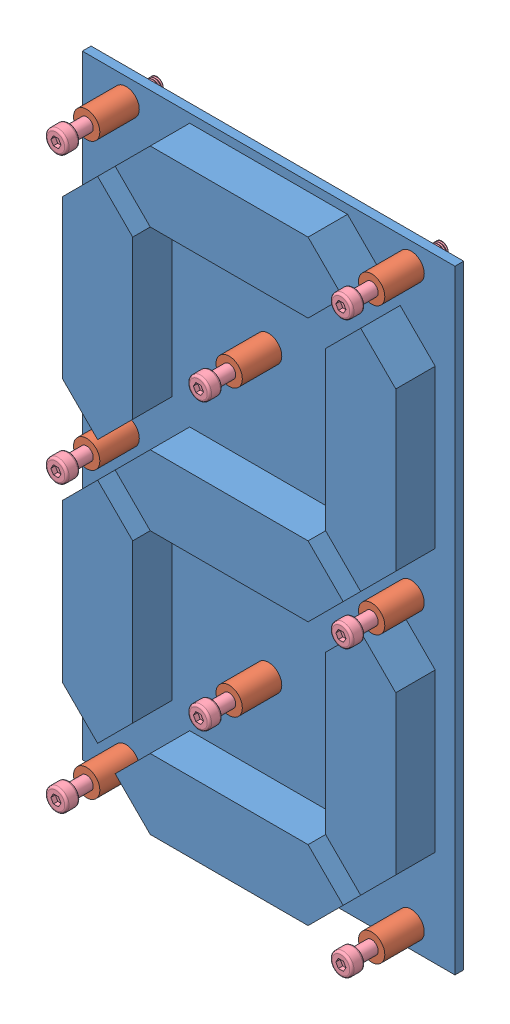
SolidWorks assembly Ensamblaje2, configuration Predeterminado. Lengths in mm.
Overall size (85 140 23).
33 component instances, 4 part files, 6 mates.
Components (placement in the parent):
- Display-1: Display [Predeterminado] at (-5.3191 -0.4666 134.5) size (85 140 11)
- Ajuste Display-1: Ajuste Display [Predeterminado] at (-37.0959 64.7634 119.0956) size (6 6 23)
  - Separador-1: Separador [Predeterminado] at (-0.7232 -0.23 17.4044) size (6 6 9)
  - Tuerca M3-1: Tuerca M3 [Predeterminado] at (-0.7232 -0.23 13.4044) x (1 0 0) z (0 -1 0) size (5.77 2 5)
  - Tornillo M3x20_CC-1: Tornillo M3x20_CC [Predeterminado] at (-0.7232 -0.23 10.4144) size (5 5 23)
- Ajuste Display-2: Ajuste Display [Predeterminado] at (-4.5959 32.2634 119.0956) size (6 6 23)
  - Separador-1: Separador [Predeterminado] at (-0.7232 -0.23 17.4044) size (6 6 9)
  - Tuerca M3-1: Tuerca M3 [Predeterminado] at (-0.7232 -0.23 13.4044) x (1 0 0) z (0 -1 0) size (5.77 2 5)
  - Tornillo M3x20_CC-1: Tornillo M3x20_CC [Predeterminado] at (-0.7232 -0.23 10.4144) size (5 5 23)
- Ajuste Display-3: Ajuste Display [Predeterminado] at (-4.5959 -32.7366 119.0956) size (6 6 23)
  - Separador-1: Separador [Predeterminado] at (-0.7232 -0.23 17.4044) size (6 6 9)
  - Tuerca M3-1: Tuerca M3 [Predeterminado] at (-0.7232 -0.23 13.4044) x (1 0 0) z (0 -1 0) size (5.77 2 5)
  - Tornillo M3x20_CC-1: Tornillo M3x20_CC [Predeterminado] at (-0.7232 -0.23 10.4144) size (5 5 23)
- Ajuste Display-4: Ajuste Display [Predeterminado] at (-37.0959 -0.2366 119.0956) size (6 6 23)
  - Separador-1: Separador [Predeterminado] at (-0.7232 -0.23 17.4044) size (6 6 9)
  - Tuerca M3-1: Tuerca M3 [Predeterminado] at (-0.7232 -0.23 13.4044) x (1 0 0) z (0 -1 0) size (5.77 2 5)
  - Tornillo M3x20_CC-1: Tornillo M3x20_CC [Predeterminado] at (-0.7232 -0.23 10.4144) size (5 5 23)
- Ajuste Display-5: Ajuste Display [Predeterminado] at (-37.0959 -65.2366 119.0956) size (6 6 23)
  - Separador-1: Separador [Predeterminado] at (-0.7232 -0.23 17.4044) size (6 6 9)
  - Tuerca M3-1: Tuerca M3 [Predeterminado] at (-0.7232 -0.23 13.4044) x (1 0 0) z (0 -1 0) size (5.77 2 5)
  - Tornillo M3x20_CC-1: Tornillo M3x20_CC [Predeterminado] at (-0.7232 -0.23 10.4144) size (5 5 23)
- Ajuste Display-6: Ajuste Display [Predeterminado] at (27.9041 64.7634 119.0956) size (6 6 23)
  - Separador-1: Separador [Predeterminado] at (-0.7232 -0.23 17.4044) size (6 6 9)
  - Tuerca M3-1: Tuerca M3 [Predeterminado] at (-0.7232 -0.23 13.4044) x (1 0 0) z (0 -1 0) size (5.77 2 5)
  - Tornillo M3x20_CC-1: Tornillo M3x20_CC [Predeterminado] at (-0.7232 -0.23 10.4144) size (5 5 23)
- Ajuste Display-7: Ajuste Display [Predeterminado] at (27.9041 -0.2366 119.0956) size (6 6 23)
  - Separador-1: Separador [Predeterminado] at (-0.7232 -0.23 17.4044) size (6 6 9)
  - Tuerca M3-1: Tuerca M3 [Predeterminado] at (-0.7232 -0.23 13.4044) x (1 0 0) z (0 -1 0) size (5.77 2 5)
  - Tornillo M3x20_CC-1: Tornillo M3x20_CC [Predeterminado] at (-0.7232 -0.23 10.4144) size (5 5 23)
- Ajuste Display-8: Ajuste Display [Predeterminado] at (27.9041 -65.2366 119.0956) size (6 6 23)
  - Separador-1: Separador [Predeterminado] at (-0.7232 -0.23 17.4044) size (6 6 9)
  - Tuerca M3-1: Tuerca M3 [Predeterminado] at (-0.7232 -0.23 13.4044) x (1 0 0) z (0 -1 0) size (5.77 2 5)
  - Tornillo M3x20_CC-1: Tornillo M3x20_CC [Predeterminado] at (-0.7232 -0.23 10.4144) size (5 5 23)
Mates (geometry in assembly coordinates):
- Concéntrica1: concentric aligned: cylinder of Display-1 through (-5.3191 32.0334 136.5) axis (0 0 -1) radius 1.25; cylinder of Ajuste Display-2/Tornillo M3x20_CC-1 through (-5.3191 32.0334 149.51) axis (0 0 -1) radius 1.5
- Concéntrica2: concentric anti-aligned: circle of Display-1; cylinder of Ajuste Display-3/Tornillo M3x20_CC-1 through (-5.3191 -32.9666 149.51) axis (0 0 -1) radius 1.5
- Coincidente1: coincident anti-aligned: plane of Display-1 through (-5.3191 -0.4666 136.5) normal (0 0 1); plane of Ajuste Display-3/Separador-1 through (-5.3191 -32.9666 136.5) normal (0 0 -1)
- Coincidente2: coincident anti-aligned: plane of Display-1 through (-5.3191 -0.4666 136.5) normal (0 0 1); plane of Ajuste Display-1/Separador-1 through (-37.8191 64.5334 136.5) normal (0 0 -1)
- Concéntrica3: concentric aligned: cylinder of Display-1 through (-37.8191 64.5334 136.5) axis (0 0 -1) radius 1.25; cylinder of Ajuste Display-1/Tornillo M3x20_CC-1 through (-37.8191 64.5334 149.51) axis (0 0 -1) radius 1.5
- Coincidente3: coincident aligned: plane of Display-1 through (-5.3191 -0.4666 136.5) normal (0 0 1); circle of Ajuste Display-2/Separador-1
